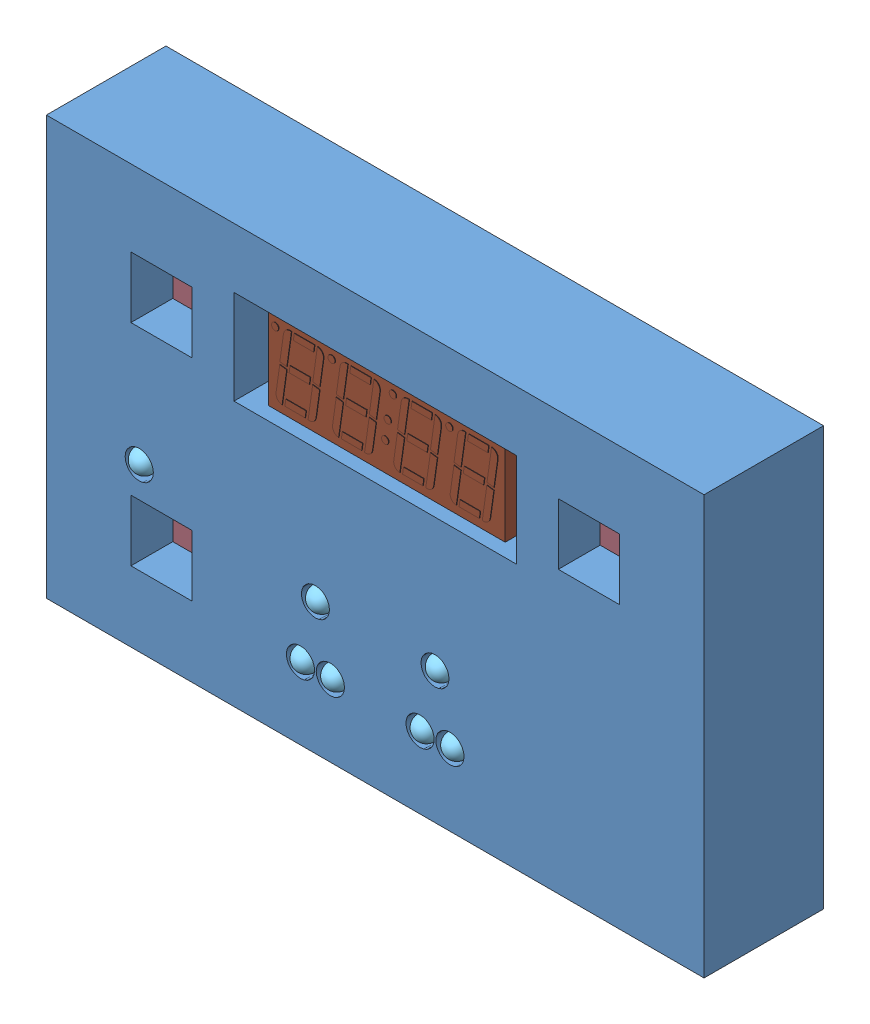
SolidWorks assembly ReceiverEndAssem, configuration Default. Lengths in mm.
Overall size (139.7 88.9 26.57).
81 component instances, 13 part files, 1 mates.
Components (placement in the parent):
- Encloseuresensorsface-1: Encloseuresensorsface [Default] at origin size (139.7 88.9 25.4)
- GolfSpeedSensor.step-1: GolfSpeedSensor.step [Default] at (-150 93.1 -3.1874) size (128.3 76.2 15.6)
  - TQFP-44_10x10mm_P0.8mm.step-1: TQFP-44_10x10mm_P0.8mm.step [Default] at (150.59 -93.35 1.65) size (12 12 1.1)
    - SOLID.step-1: SOLID.step [Default] at origin size (12 12 1.1)
  - R_Axial_DIN0207_L6.3mm_D2.5mm_P10.16mm_Horizontal.step-1: R_Axial_DIN0207_L6.3mm_D2.5mm_P10.16mm_Horizontal.step [Default] at (180.01 -84.25 1.65) size (10.76 2.5 5.5)
    - SOLID-0.step-1: SOLID-0.step [Default] at origin size (10.76 2.5 5.5)
  - USB_Mini-B_Lumberg_2486_01_Horizontal.step-1: USB_Mini-B_Lumberg_2486_01_Horizontal.step [Default] at (91 -91.775 1.65) x (0 -1 0) z (0 0 1) size (9.9 9.21 5)
    - SOLID-1.step-1: SOLID-1.step [Default] at origin size (9.9 9.21 5)
  - LED_D5.0mm_Clear.step-1: LED_D5.0mm_Clear.step [Default] at (160.865 -122.25 1.65) x (-1 0 0) z (0 0 1) size (5.4 5.8 14.1)
    - SOLID-2.step-1: SOLID-2.step [Default] at origin size (5.4 5.8 14.1)
  - Crystal_SMD_Abracon_ABM8G-4Pin_3.2x2.5mm.step-1: Crystal_SMD_Abracon_ABM8G-4Pin_3.2x2.5mm.step [Default] at (150.59 -104.55 1.65) x (-1 0 0) z (0 0 1) size (3.2 2.5 0.64)
    - SOLID-3.step-1: SOLID-3.step [Default] at origin size (3.2 2.5 0.64)
  - R_Axial_DIN0207_L6.3mm_D2.5mm_P10.16mm_Horizontal.step-2: R_Axial_DIN0207_L6.3mm_D2.5mm_P10.16mm_Horizontal.step [Default] at (180.01 -94.75 1.65) size (10.76 2.5 5.5)
    - SOLID-0.step-1: SOLID-0.step [Default] at origin size (10.76 2.5 5.5)
  - R_Axial_DIN0207_L6.3mm_D2.5mm_P10.16mm_Horizontal.step-3: R_Axial_DIN0207_L6.3mm_D2.5mm_P10.16mm_Horizontal.step [Default] at (180.01 -87.75 1.65) size (10.76 2.5 5.5)
    - SOLID-0.step-1: SOLID-0.step [Default] at origin size (10.76 2.5 5.5)
  - PinSocket_1x03_P2.54mm_Horizontal.step-1: PinSocket_1x03_P2.54mm_Horizontal.step [Default] at (194.4 -117.175 1.65) size (10.13 7.62 5.84)
    - SOLID-4.step-1: SOLID-4.step [Default] at origin size (10.13 7.62 5.84)
  - R_Axial_DIN0207_L6.3mm_D2.5mm_P10.16mm_Horizontal.step-4: R_Axial_DIN0207_L6.3mm_D2.5mm_P10.16mm_Horizontal.step [Default] at (101.62 -89.825 1.65) size (10.76 2.5 5.5)
    - SOLID-0.step-1: SOLID-0.step [Default] at origin size (10.76 2.5 5.5)
  - R_Axial_DIN0207_L6.3mm_D2.5mm_P10.16mm_Horizontal.step-5: R_Axial_DIN0207_L6.3mm_D2.5mm_P10.16mm_Horizontal.step [Default] at (128.51 -103.35 1.65) size (10.76 2.5 5.5)
    - SOLID-0.step-1: SOLID-0.step [Default] at origin size (10.76 2.5 5.5)
  - LED_D5.0mm_Clear.step-2: LED_D5.0mm_Clear.step [Default] at (161.55 -109.45 1.65) size (5.4 5.8 14.1)
    - SOLID-2.step-1: SOLID-2.step [Default] at origin size (5.4 5.8 14.1)
  - R_Axial_DIN0207_L6.3mm_D2.5mm_P10.16mm_Horizontal.step-6: R_Axial_DIN0207_L6.3mm_D2.5mm_P10.16mm_Horizontal.step [Default] at (146.7 -112.17 1.65) x (0 -1 0) z (0 0 1) size (10.76 2.5 5.5)
    - SOLID-0.step-1: SOLID-0.step [Default] at origin size (10.76 2.5 5.5)
  - SOT-23-6.step-1: SOT-23-6.step [Default] at (118.45 -91.375 1.65) size (2.8 2.9 1.55)
    - SOLID-5.step-1: SOLID-5.step [Default] at origin size (2.8 2.9 1.55)
  - R_Axial_DIN0207_L6.3mm_D2.5mm_P10.16mm_Horizontal.step-7: R_Axial_DIN0207_L6.3mm_D2.5mm_P10.16mm_Horizontal.step [Default] at (153.4 -112.22 1.65) x (0 -1 0) z (0 0 1) size (10.76 2.5 5.5)
    - SOLID-0.step-1: SOLID-0.step [Default] at origin size (10.76 2.5 5.5)
  - R_Axial_DIN0207_L6.3mm_D2.5mm_P10.16mm_Horizontal.step-8: R_Axial_DIN0207_L6.3mm_D2.5mm_P10.16mm_Horizontal.step [Default] at (172.79 -119.73 1.65) x (0 1 0) z (0 0 1) size (10.76 2.5 5.5)
    - SOLID-0.step-1: SOLID-0.step [Default] at origin size (10.76 2.5 5.5)
  - R_Axial_DIN0207_L6.3mm_D2.5mm_P10.16mm_Horizontal.step-9: R_Axial_DIN0207_L6.3mm_D2.5mm_P10.16mm_Horizontal.step [Default] at (180.01 -98.25 1.65) size (10.76 2.5 5.5)
    - SOLID-0.step-1: SOLID-0.step [Default] at origin size (10.76 2.5 5.5)
  - R_Axial_DIN0207_L6.3mm_D2.5mm_P10.16mm_Horizontal.step-10: R_Axial_DIN0207_L6.3mm_D2.5mm_P10.16mm_Horizontal.step [Default] at (101.62 -92.925 1.65) size (10.76 2.5 5.5)
    - SOLID-0.step-1: SOLID-0.step [Default] at origin size (10.76 2.5 5.5)
  - LED_D5.0mm_Clear.step-3: LED_D5.0mm_Clear.step [Default] at (98.45 -102.95 1.65) size (5.4 5.8 14.1)
    - SOLID-2.step-1: SOLID-2.step [Default] at origin size (5.4 5.8 14.1)
  - LED_D5.0mm_Clear.step-4: LED_D5.0mm_Clear.step [Default] at (164.815 -122.25 1.65) size (5.4 5.8 14.1)
    - SOLID-2.step-1: SOLID-2.step [Default] at origin size (5.4 5.8 14.1)
  - LED_D5.0mm_Clear.step-5: LED_D5.0mm_Clear.step [Default] at (136.115 -109.55 1.65) size (5.4 5.8 14.1)
    - SOLID-2.step-1: SOLID-2.step [Default] at origin size (5.4 5.8 14.1)
  - PinSocket_2x03_P2.54mm_Vertical.step-1: PinSocket_2x03_P2.54mm_Vertical.step [Default] at (92.49 -103.775 1.65) size (5.08 7.62 10.1)
    - SOLID-6.step-1: SOLID-6.step [Default] at origin size (5.08 7.62 10.1)
  - R_Axial_DIN0207_L6.3mm_D2.5mm_P10.16mm_Horizontal.step-11: R_Axial_DIN0207_L6.3mm_D2.5mm_P10.16mm_Horizontal.step [Default] at (128.1 -112.12 1.65) x (0 -1 0) z (0 0 1) size (10.76 2.5 5.5)
    - SOLID-0.step-1: SOLID-0.step [Default] at origin size (10.76 2.5 5.5)
  - R_Axial_DIN0207_L6.3mm_D2.5mm_P10.16mm_Horizontal.step-12: R_Axial_DIN0207_L6.3mm_D2.5mm_P10.16mm_Horizontal.step [Default] at (180.01 -105.25 1.65) size (10.76 2.5 5.5)
    - SOLID-0.step-1: SOLID-0.step [Default] at origin size (10.76 2.5 5.5)
  - LED_D5.0mm_Clear.step-6: LED_D5.0mm_Clear.step [Default] at (139.315 -122.25 1.65) size (5.4 5.8 14.1)
    - SOLID-2.step-1: SOLID-2.step [Default] at origin size (5.4 5.8 14.1)
  - R_Axial_DIN0207_L6.3mm_D2.5mm_P10.16mm_Horizontal.step-13: R_Axial_DIN0207_L6.3mm_D2.5mm_P10.16mm_Horizontal.step [Default] at (180.01 -101.65 1.65) size (10.76 2.5 5.5)
    - SOLID-0.step-1: SOLID-0.step [Default] at origin size (10.76 2.5 5.5)
  - R_Axial_DIN0207_L6.3mm_D2.5mm_P10.16mm_Horizontal.step-14: R_Axial_DIN0207_L6.3mm_D2.5mm_P10.16mm_Horizontal.step [Default] at (158.02 -115.7 1.65) size (10.76 2.5 5.5)
    - SOLID-0.step-1: SOLID-0.step [Default] at origin size (10.76 2.5 5.5)
  - CP_Radial_D5.0mm_P2.50mm.step-1: CP_Radial_D5.0mm_P2.50mm.step [Default] at (139.7951 -96.85 1.65) x (-1 0 0) z (0 0 1) size (6.13 6.52 7)
    - SOLID-7.step-1: SOLID-7.step [Default] at origin size (6.13 6.52 7)
  - CA56-12EWA.step-1: CA56-12EWA.step [Default] at (156.49 -63.71 1.65) x (0 -1 0) z (0 0 1) size (19 50.3 12.2)
    - SOLID-8.step-1: SOLID-8.step [Default] at origin size (19 50.3 12.2)
  - R_Axial_DIN0207_L6.3mm_D2.5mm_P10.16mm_Horizontal.step-15: R_Axial_DIN0207_L6.3mm_D2.5mm_P10.16mm_Horizontal.step [Default] at (116.67 -102.95 1.65) x (-1 0 0) z (0 0 1) size (10.76 2.5 5.5)
    - SOLID-0.step-1: SOLID-0.step [Default] at origin size (10.76 2.5 5.5)
  - CP_Radial_D5.0mm_P2.50mm.step-2: CP_Radial_D5.0mm_P2.50mm.step [Default] at (139.6951 -85.55 1.65) x (-1 0 0) z (0 0 1) size (6.13 6.52 7)
    - SOLID-7.step-1: SOLID-7.step [Default] at origin size (6.13 6.52 7)
  - CP_Radial_D5.0mm_P2.50mm.step-3: CP_Radial_D5.0mm_P2.50mm.step [Default] at (156.39 -103.0449 1.65) x (0 -1 0) z (0 0 1) size (6.13 6.52 7)
    - SOLID-7.step-1: SOLID-7.step [Default] at origin size (6.13 6.52 7)
  - R_Axial_DIN0207_L6.3mm_D2.5mm_P10.16mm_Horizontal.step-16: R_Axial_DIN0207_L6.3mm_D2.5mm_P10.16mm_Horizontal.step [Default] at (91.79 -73.83 1.65) x (0 1 0) z (0 0 1) size (10.76 2.5 5.5)
    - SOLID-0.step-1: SOLID-0.step [Default] at origin size (10.76 2.5 5.5)
  - R_Axial_DIN0207_L6.3mm_D2.5mm_P10.16mm_Horizontal.step-17: R_Axial_DIN0207_L6.3mm_D2.5mm_P10.16mm_Horizontal.step [Default] at (207.39 -73.83 1.65) x (0 1 0) z (0 0 1) size (10.76 2.5 5.5)
    - SOLID-0.step-1: SOLID-0.step [Default] at origin size (10.76 2.5 5.5)
  - DIP-16_W7.62mm_Socket.step-1: DIP-16_W7.62mm_Socket.step [Default] at (173 -102.48 1.65) x (-1 0 0) z (0 0 1) size (10.16 20.32 7.79)
    - SOLID-9.step-1: SOLID-9.step [Default] at origin size (10.16 20.32 7.79)
  - CP_Radial_D5.0mm_P2.50mm.step-4: CP_Radial_D5.0mm_P2.50mm.step [Default] at (144.69 -105.5551 1.65) x (0 1 0) z (0 0 1) size (6.13 6.52 7)
    - SOLID-7.step-1: SOLID-7.step [Default] at origin size (6.13 6.52 7)
  - R_Axial_DIN0207_L6.3mm_D2.5mm_P10.16mm_Horizontal.step-18: R_Axial_DIN0207_L6.3mm_D2.5mm_P10.16mm_Horizontal.step [Default] at (180.01 -91.35 1.65) size (10.76 2.5 5.5)
    - SOLID-0.step-1: SOLID-0.step [Default] at origin size (10.76 2.5 5.5)
  - R_Axial_DIN0207_L6.3mm_D2.5mm_P10.16mm_Horizontal.step-19: R_Axial_DIN0207_L6.3mm_D2.5mm_P10.16mm_Horizontal.step [Default] at (180.01 -108.75 1.65) size (10.76 2.5 5.5)
    - SOLID-0.step-1: SOLID-0.step [Default] at origin size (10.76 2.5 5.5)
  - LED_D5.0mm_Clear.step-7: LED_D5.0mm_Clear.step [Default] at (135.365 -122.25 1.65) x (-1 0 0) z (0 0 1) size (5.4 5.8 14.1)
    - SOLID-2.step-1: SOLID-2.step [Default] at origin size (5.4 5.8 14.1)
  - R_Axial_DIN0207_L6.3mm_D2.5mm_P10.16mm_Horizontal.step-20: R_Axial_DIN0207_L6.3mm_D2.5mm_P10.16mm_Horizontal.step [Default] at (91.2 -113.42 1.65) x (0 -1 0) z (0 0 1) size (10.76 2.5 5.5)
    - SOLID-0.step-1: SOLID-0.step [Default] at origin size (10.76 2.5 5.5)
  - PCB.step-1: PCB.step [Default] at origin size (126.9 76.2 1.6)
Mates (geometry in assembly coordinates):
- Parallel6: parallel anti-aligned: plane of Encloseuresensorsface-1 through (0 0 0) normal (0 0 -1); plane of GolfSpeedSensor.step-1/PCB.step-1 through (0.0656 0.025 -1.5874) normal (0 0 1)
